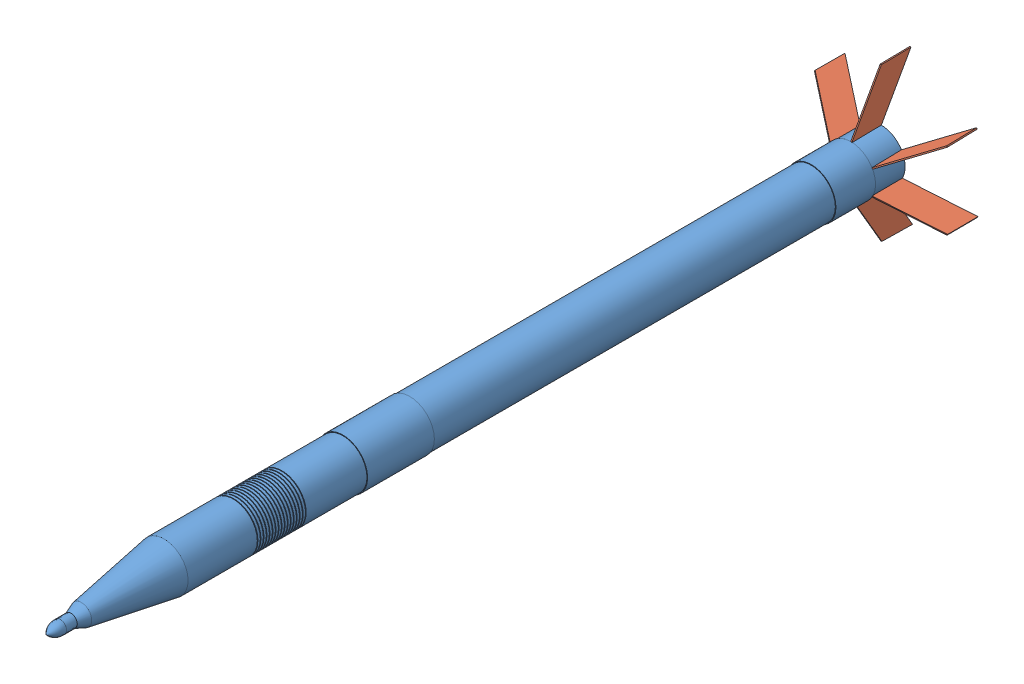
SolidWorks assembly S8KOM, configuration Default. Lengths in mm.
Overall size (221.59 253.21 1434.01).
7 component instances, 2 part files, 5 mates.
Components (placement in the parent):
- S8_Body-1: S8_Body [Default] at origin size (82 82 1384)
- S8KOMStab-1: S8KOMStab [Default] at (-0.5635 40 -1333.9864) x (0.999848 0 -0.017452) z (0.017452 0 0.999848) size (2 86.6 100)
- S8KOMStab-2: S8KOMStab [Default] at (34.3592 20.488 -1333.9864) x (0.499924 -0.865894 -0.017452) z (0.008726 -0.015114 0.999848) size (2 86.6 100)
- S8KOMStab-3: S8KOMStab [Default] at (34.9228 -19.512 -1333.9864) x (-0.499924 -0.865894 -0.017452) z (-0.008726 -0.015114 0.999848) size (2 86.6 100)
- S8KOMStab-4: S8KOMStab [Default] at (0.5635 -40 -1333.9864) x (-0.999848 0 -0.017452) z (-0.017452 0 0.999848) size (2 86.6 100)
- S8KOMStab-5: S8KOMStab [Default] at (-34.3592 -20.488 -1333.9864) x (-0.499924 0.865894 -0.017452) z (-0.008726 0.015114 0.999848) size (2 86.6 100)
- S8KOMStab-6: S8KOMStab [Default] at (-34.9228 19.512 -1333.9864) x (0.499924 0.865894 -0.017452) z (0.008726 0.015114 0.999848) size (2 86.6 100)
Mates (geometry in assembly coordinates):
- Concentric1: concentric anti-aligned: cylinder of S8_Body-1 through (0 38 -1359) axis (0 1 0) radius 0.25; cylinder of S8KOMStab-1 through (0 42 -1359) axis (0 -1 0) radius 0.5
- Tangent3: tangent anti-aligned: cylinder of S8_Body-1 through (0 0 0) axis (0 0 1) radius 40; plane of S8KOMStab-1 through (1.4362 40 -1334.0213) normal (0 -1 0)
- Coincident6: coordinate: point of S8_Body-1
- Coincident7: coincident aligned: plane of S8_Body-1 through (0 0 0) normal (1 0 0)
- Coincident8: coincident aligned: plane of S8_Body-1 through (0 0 0) normal (0 1 0)
